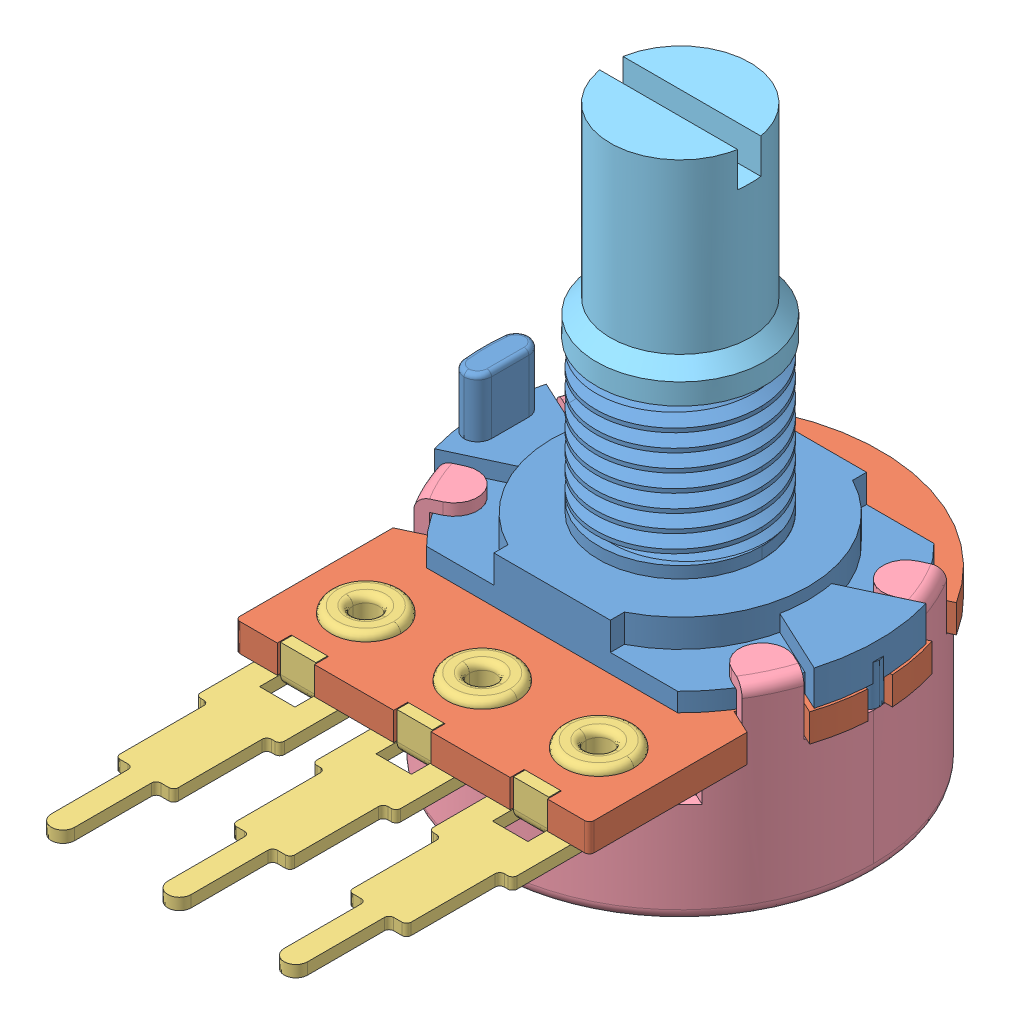
SolidWorks assembly AARL_QR_EL_PT_000-P160KN26L, configuration Default. Lengths in mm.
Overall size (17.17 24.63 30.6).
7 component instances, 5 part files, 18 mates.
Components (placement in the parent):
- AARL_QR_EL_PT_001-1: AARL_QR_EL_PT_001 [Default] at origin size (17.1 9.45 11)
- AARL_QR_EL_PT_002-1: AARL_QR_EL_PT_002 [Default] at origin size (17.17 1.2 20.1)
- AARL_QR_EL_PT_003-1: AARL_QR_EL_PT_003 [Default] at (-10 0 0) size (3.6 2 15.3)
- AARL_QR_EL_PT_003-2: AARL_QR_EL_PT_003 [Default] at (-5 0 0) size (3.6 2 15.3)
- AARL_QR_EL_PT_003-3: AARL_QR_EL_PT_003 [Default] at origin size (3.6 2 15.3)
- AARL_QR_EL_PT_004-1: AARL_QR_EL_PT_004 [Default] at origin size (16.6 8.71 16.6)
- AARL_QR_EL_PT_005-1: AARL_QR_EL_PT_005 [Default] at (0 7.7 0) size (7.2 16.83 7.2)
Mates (geometry in assembly coordinates):
- Concentric1: concentric anti-aligned: cylinder of AARL_Puppy_18_03_06_004-1 through (0 -8.2 0) axis (0 1 0) radius 7.8; cylinder of AARL_Puppy_18_03_06_002-1 through (0 -0.8 0) axis (0 -1 0) radius 3.05
- Width1: width anti-aligned: plane of AARL_Puppy_18_03_06_002-1 through (-7.2788 -0.8 -4.5803) normal (-0.422618 0 0.906308); plane of AARL_Puppy_18_03_06_004-1 through (-7.4561 -0.8 -2.2907) normal (0.422618 0 -0.906308); plane of AARL_Puppy_18_03_06_002-1 through (-6.5882 -2 -4.1755) normal (0.422618 0 -0.906308); plane of AARL_Puppy_18_03_06_004-1 through (-7.8902 -2 -2.5759) normal (-0.422618 0 0.906308)
- Coincident1: coincident anti-aligned: plane of AARL_Puppy_18_03_06_004-1 through (0 -2 0) normal (0 1 0); plane of AARL_Puppy_18_03_06_002-1 through (0 -2 0) normal (0 -1 0)
- Concentric2: concentric aligned: cylinder of AARL_Puppy_18_03_06_002-1 through (0 -0.8 0) axis (0 -1 0) radius 3.05; cylinder of AARL_Puppy_18_03_06_001-1 through (0 7.7 0) axis (0 -1 0) radius 2
- Width2: width anti-aligned: plane of AARL_Puppy_18_03_06_001-1 through (-8.1533 0 2.403) normal (0.422618 0 0.906308); plane of AARL_Puppy_18_03_06_004-1 through (-5.3863 0 -1.1127) normal (0.422618 0 -0.906308); plane of AARL_Puppy_18_03_06_001-1 through (-7.4335 -2 2.3629) normal (-0.422618 0 -0.906308); plane of AARL_Puppy_18_03_06_004-1 through (-7.8902 -2 -2.5759) normal (-0.422618 0 0.906308)
- Coincident2: coincident anti-aligned: plane of AARL_Puppy_18_03_06_002-1 through (0 -0.8 0) normal (0 1 0); plane of AARL_Puppy_18_03_06_001-1 through (0 -0.8 0) normal (0 -1 0)
- Concentric3: concentric aligned: cylinder of AARL_Puppy_18_03_06_002-1 through (-5 -0.8 8.5) axis (0 1 0) radius 0.95; cylinder of AARL_Puppy_18_03_06_003-1 through (-5 -2.075 8.5) axis (0 1 0) radius 0.9
- Coincident3: coincident anti-aligned: plane of AARL_Puppy_18_03_06_002-1 through (0 -2 0) normal (0 -1 0); plane of AARL_Puppy_18_03_06_003-1 through (-5 -2 8.5) normal (0 1 0)
- Width3: width aligned: plane of AARL_Puppy_18_03_06_003-1 through (-5.76 -2.5 11.4) normal (-1 0 0); plane of AARL_Puppy_18_03_06_002-1 through (-4.24 -2.5 10.9) normal (1 0 0); plane of AARL_Puppy_18_03_06_003-1 through (-4.2 -0.8 11.5) normal (-1 0 0); plane of AARL_Puppy_18_03_06_002-1 through (-5.8 -0.8 10.9) normal (1 0 0)
- Coincident4: coincident anti-aligned: plane of AARL_Puppy_18_03_06_002-1 through (0 -2 0) normal (0 -1 0); plane of AARL_Puppy_18_03_06_003-2 through (0 -2 8.5) normal (0 1 0)
- Width4: width anti-aligned: plane of AARL_Puppy_18_03_06_003-2 through (0.76 -2.5 10.9) normal (1 0 0); plane of AARL_Puppy_18_03_06_002-1 through (-0.76 -2.5 11.4) normal (-1 0 0); plane of AARL_Puppy_18_03_06_003-2 through (0.8 -0.8 11.5) normal (-1 0 0); plane of AARL_Puppy_18_03_06_002-1 through (-0.8 -0.8 10.9) normal (1 0 0)
- Concentric4: concentric aligned: cylinder of AARL_Puppy_18_03_06_002-1 through (0 -0.8 8.5) axis (0 1 0) radius 0.95; cylinder of AARL_Puppy_18_03_06_003-2 through (0 -2.075 8.5) axis (0 1 0) radius 0.9
- Coincident5: coincident anti-aligned: plane of AARL_Puppy_18_03_06_002-1 through (0 -2 0) normal (0 -1 0); plane of AARL_Puppy_18_03_06_003-3 through (5 -2 8.5) normal (0 1 0)
- Width5: width anti-aligned: plane of AARL_Puppy_18_03_06_003-3 through (5.76 -2.5 10.9) normal (1 0 0); plane of AARL_Puppy_18_03_06_002-1 through (4.24 -2.5 11.4) normal (-1 0 0); plane of AARL_Puppy_18_03_06_003-3 through (5.8 -0.8 11.5) normal (-1 0 0); plane of AARL_Puppy_18_03_06_002-1 through (4.2 -0.8 10.9) normal (1 0 0)
- Concentric5: concentric aligned: cylinder of AARL_Puppy_18_03_06_002-1 through (5 -0.8 8.5) axis (0 1 0) radius 0.95; cylinder of AARL_Puppy_18_03_06_003-3 through (5 -2.075 8.5) axis (0 1 0) radius 0.9
- Concentric6: concentric anti-aligned: cylinder of AARL_Puppy_18_03_06_001-1 through (0 7.7 0) axis (0 -1 0) radius 2; cylinder of AARL_Puppy_18_03_06_006-1 through (0 51.0234 0) axis (0 1 0) radius 2
- Coincident6: coincident anti-aligned: plane of AARL_Puppy_18_03_06_001-1 through (0 7.7 0) normal (0 1 0); plane of AARL_Puppy_18_03_06_006-1 through (2 7.7 0) normal (0 -1 0)
- Parallel1: parallel aligned: plane of AARL_Puppy_18_03_06_001-1 through (5.3889 0 -5.5) normal (0 0 -1); plane of AARL_Puppy_18_03_06_006-1 through (-3 14.9313 0.5) normal (0 0 -1)
